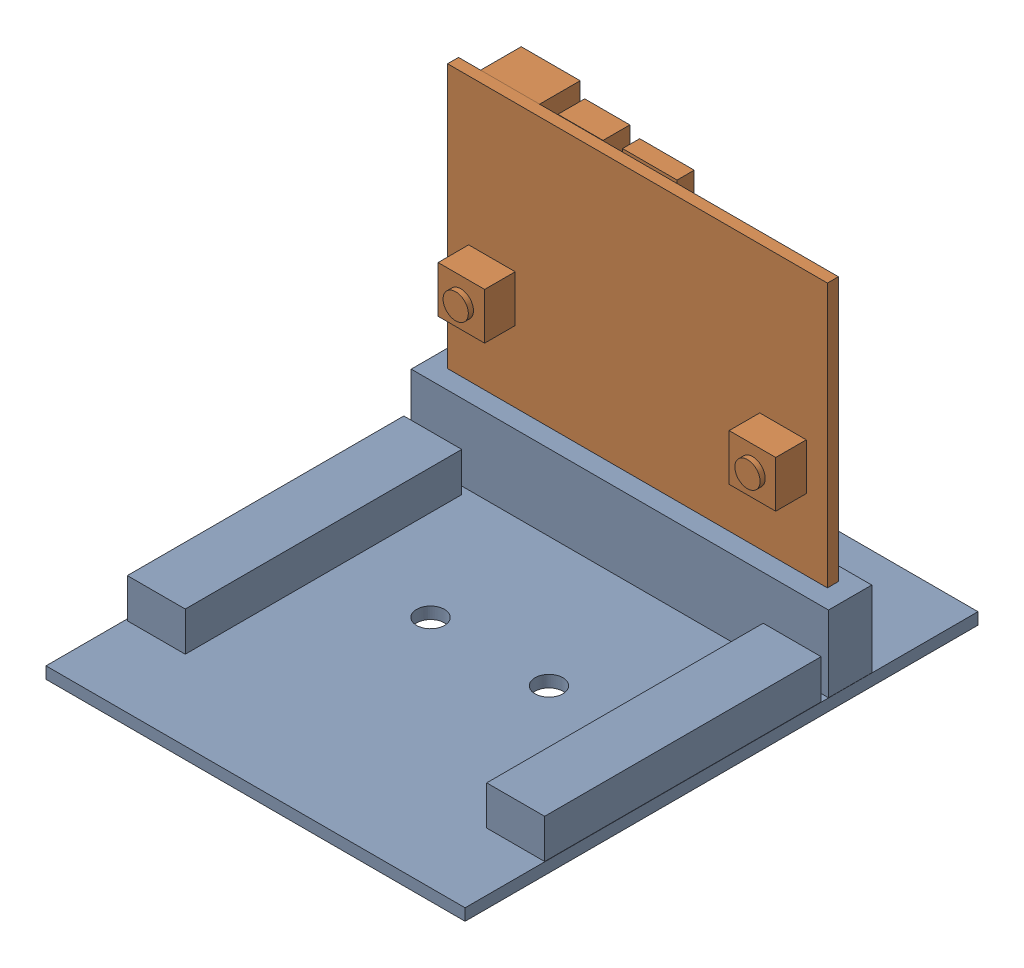
SolidWorks assembly assemblage carte micro bit et carte moteur, configuration Défaut. Lengths in mm.
Overall size (57.15 48.37 69.94).
2 component instances, 2 part files, 0 mates.
Components (placement in the parent):
- carte moteur micro bit-2: carte moteur micro bit [Défaut] at (-32.1793 -5.7313 1069.9356) size (57.15 11.96 69.94)
- carte microbit-2: carte microbit [Défaut] at (22.256 42.2274 1017.8205) x (-1 0 0) z (0 1 0) size (51.8 11.92 42.41)
